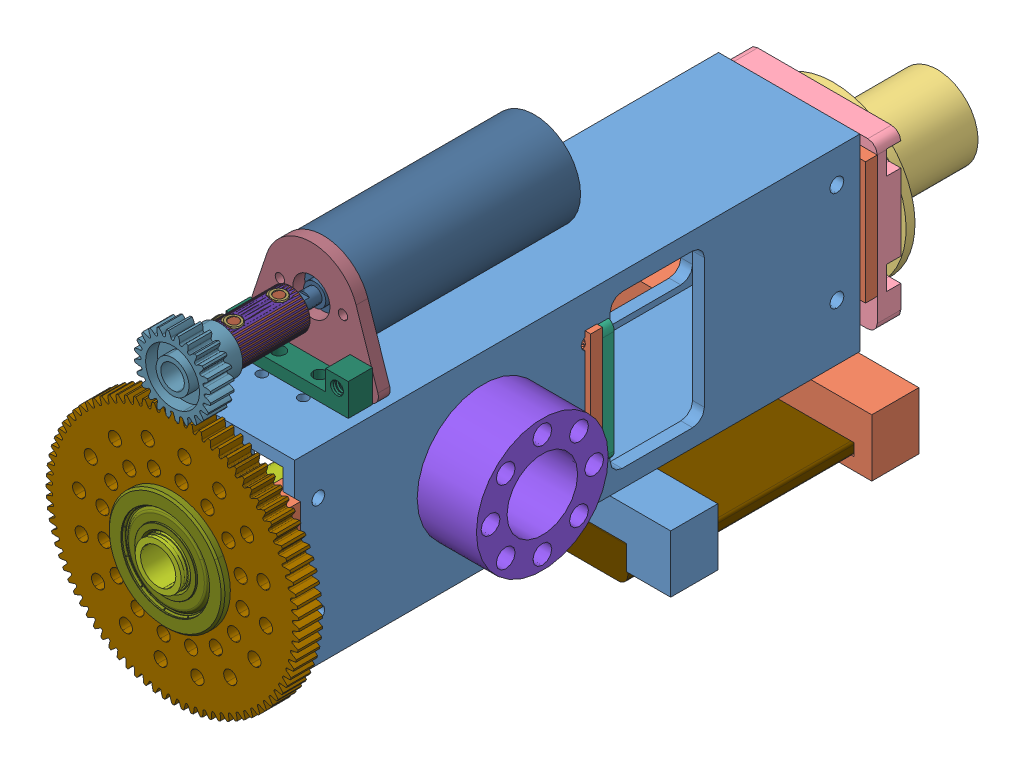
SolidWorks assembly L3v3 Assembly, configuration Default. Lengths in mm.
Overall size (93.13 102.39 210.1).
34 component instances, 20 part files, 64 mates.
Components (placement in the parent):
- L3v1 Base-1: L3v1 Base [Default] at (8.4803 58.2755 10.2579) x (1 0 0) z (0 -1 0) size (38.1 152.4 50.8)
- J2v2 Angle Bracket 585508-1: J2v2 Angle Bracket 585508 [Default] at (25.1173 61.4505 10.2579) x (0 -1 0) z (1 0 0) size (33.02 12.43 7.88)
- J2v2 Angle Bracket 585508-2: J2v2 Angle Bracket 585508 [Default] at (-8.1567 61.4505 10.2579) x (0 1 0) z (-1 0 0) size (33.02 12.43 7.88)
- 12 wire slip ring-1: 12 wire slip ring [Default] at (8.4803 58.2755 -1.6671) x (0.999999 -0.001711 0) z (-0.001711 -0.999999 0) size (44 39.4 44)
- L3v1 SlipRingBlock-2: L3v1 SlipRingBlock [Default] at (8.4803 58.2755 7.0829) x (-1 0 0) z (0 -1 0) size (41.15 6.35 44.45)
- 0.5 oilite bushing-1: 0.5 oilite bushing [6338K572] at (8.4803 58.2755 76.4249) x (1 0 0) z (0 -1 0) size (22.23 12.7 22.23)
- J2v2 Angle Bracket 585508-3: J2v2 Angle Bracket 585508 [Default] at (25.1173 58.2755 84.3624) x (0 -1 0) z (1 0 0) size (33.02 12.43 7.88)
- J2v2 Angle Bracket 585508-4: J2v2 Angle Bracket 585508 [Default] at (-8.1567 58.2755 84.3624) x (0 1 0) z (-1 0 0) size (33.02 12.43 7.88)
- L3v1 Bushing Support-1: L3v1 Bushing Support [Default] at (8.4803 58.2755 78.0124) x (1 0 0) z (0 -1 0) size (41.15 3.17 33.02)
- Link3 to 4 Shaft-1: Link3 to 4 Shaft [Default] at (8.4803 58.2755 127.4789) x (0 0 -1) z (0.966023 0.258455 0) size (105.92 12.45 12.45)
- L3v1 Spacer-1: L3v1 Spacer [Default] at (43.5069 58.2755 111.8579) x (0 1 0) z (0 0 1) size (35.56 15.98 35.56)
- 0.5 oilite bushing-2: 0.5 oilite bushing [6338K572] at (8.4803 58.2755 170.5954) x (1 0 0) z (0 1 0) size (22.23 12.7 22.23)
- 84T 32DP 1in bore plate gear-1: 84T 32DP 1in bore plate gear [Default] at (8.4803 58.2755 176.5517) x (-0.495933 -0.868361 0) z (0 0 -1) size (68.26 68.26 6.35)
- 56 rpm motor-1: 56 rpm motor [Default] at (8.4803 100.6135 135.9258) x (0 0 1) z (-1 0 0) size (74.8 24.8 24.8)
- 4mm to 6mm-1: 4mm to 6mm [Default] at (21.5273 122.4162 168.6055) x (0.389298 0.921112 0) z (-0.921112 0.389298 0) size (10.67 19.05 10.93)
  - 625220 assembly.STEP-1: 625220 assembly.STEP [Default] at origin size (10.67 19.05 10.93)
    - 625220.STEP-1: 625220.STEP [Default] at (-25.1618 4.7538 3.53) size (10.67 19.05 10.67)
    - 632134_91375A436.STEP-1: 632134_91375A436.STEP [Default] at (-25.1618 8.1828 7.9297) x (-0.317738 0.948179 0) z (0 0 1) size (4.83 4.83 3.18)
    - 632134_91375A436.STEP-2: 632134_91375A436.STEP [Default] at (-25.1618 20.3748 6.6171) x (0.993493 0.113893 0) z (0 0 1) size (4.83 4.83 3.18)
- L3v1 Bushing Support-2: L3v1 Bushing Support [Default] at (8.4803 58.2755 169.0079) x (1 0 0) z (0 1 0) size (41.15 3.17 33.02)
- L3 motor mount v2-2: L3 motor mount v2 [Default] at (8.4803 100.6135 139.1008) x (0 0 1) z (-1 0 0) size (3.17 29.64 36.13)
- J2v2 Angle Bracket 585508-9: J2v2 Angle Bracket 585508 [Default] at (-8.1567 58.2755 162.6579) x (0 -1 0) z (-1 0 0) size (33.02 12.43 7.88)
- J2v2 Angle Bracket 585508-10: J2v2 Angle Bracket 585508 [Default] at (25.1173 58.2755 162.6579) x (0 1 0) z (1 0 0) size (33.02 12.43 7.88)
- 24T quarter inch gear hub-1: 24T quarter inch gear hub [Default] at (18.8185 127.1627 171.0724) x (-0.383066 0.923721 0) z (0 0 1) size (20.64 20.64 12.7)
- DualPanelMountA-1: DualPanelMountA [Default] at (-8.0297 83.6755 139.1008) x (1 0 0) z (0 -1 0) size (33.02 6.58 8.63)
- .5ID 1.125OD Flange Bearing-1: .5ID 1.125OD Flange Bearing [Default] at (8.4803 58.2755 170.5954) x (-0.477964 0.87838 0) z (0.87838 0.477964 0) size (31.17 7.94 31.17)
- 4mm to .25in-1: 4mm to .25in [Default] at (94.8379 57.4084 170.9593) x (0.996664 -0.081613 0) z (0.081613 0.996664 0) size (10.67 19.05 10.67)
  - 625118 assembly.STEP-1: 625118 assembly.STEP [Default] at origin size (10.67 19.05 10.67)
    - 625118.STEP-1: 625118.STEP [Default] at (-89.5957 7.0024 36.013) size (10.67 19.05 10.67)
    - 632134_91375A436.STEP-1: 632134_91375A436.STEP [Default] at (-89.5957 10.4314 40.1568) x (0.259519 -0.965738 0) z (0 0 1) size (4.83 4.83 3.18)
    - 632134_91375A436.STEP-2: 632134_91375A436.STEP [Default] at (-89.5957 22.6234 40.1568) x (0.166108 -0.986108 0) z (0 0 1) size (4.83 4.83 3.18)
- SlidingMount-1: SlidingMount [Default] at (8.4803 23.9855 13.848) x (-1 0 0) z (0 1 0) size (60.96 76.2 10.16)
- camerasliderailstopper-1: camerasliderailstopper [Default] at (48.4853 32.8755 64.9589) x (0 0 1) z (1 0 0) size (12.7 15.49 70.87)
- camerasliderail-1: camerasliderail [Default] at (48.4853 32.8755 10.7246) x (0 0 1) z (1 0 0) size (12.7 15.49 70.87)
Mates (geometry in assembly coordinates):
- Coincident5: coincident anti-aligned: plane of L3v1 Base-1 through (8.4803 58.2755 10.2579) normal (0 0 -1); plane of J2v2 Angle Bracket 585508-1 through (25.1173 61.4505 10.2579) normal (0 0 1)
- Coincident7: coincident anti-aligned: plane of L3v1 Base-1 through (24.3553 36.0505 162.6579) normal (-1 0 0); plane of J2v2 Angle Bracket 585508-1 through (24.3553 51.0213 19.5136) normal (1 0 0)
- Coincident8: coincident anti-aligned: plane of L3v1 Base-1 through (-7.3947 36.0505 162.6579) normal (1 0 0); plane of J2v2 Angle Bracket 585508-2 through (-7.3947 71.8798 19.5136) normal (-1 0 0)
- Coincident9: coincident anti-aligned: plane of L3v1 Base-1 through (8.4803 58.2755 10.2579) normal (0 0 -1); plane of J2v2 Angle Bracket 585508-2 through (-8.1567 61.4505 10.2579) normal (0 0 1)
- Coincident10: coincident aligned: plane of J2v2 Angle Bracket 585508-1 through (29.0543 77.9605 7.0829) normal (0 1 0); plane of J2v2 Angle Bracket 585508-2 through (-12.0937 77.9605 7.0829) normal (0 1 0)
- Distance2: distance = 5.715 mm aligned: plane of J2v2 Angle Bracket 585508-1 through (29.0543 77.9605 7.0829) normal (0 1 0); plane of L3v1 Base-1 through (-10.5697 83.6755 162.6579) normal (0 1 0)
- Coincident16: coincident anti-aligned: plane of J2v2 Angle Bracket 585508-1 through (25.1173 61.4505 7.0829) normal (0 0 -1); plane of L3v1 SlipRingBlock-2 through (8.4803 58.2755 7.0829) normal (0 0 1)
- Concentric4: concentric anti-aligned: circle of J2v2 Angle Bracket 585508-1; cylinder of L3v1 SlipRingBlock-2 through (25.8793 74.9209 0.7329) axis (0 0 -1) radius 1.8986
- Concentric5: concentric anti-aligned: circle of J2v2 Angle Bracket 585508-2; circle of L3v1 SlipRingBlock-2
- Coincident17: coincident anti-aligned: plane of 12 wire slip ring-1 through (8.4803 58.2755 0.7329) normal (0 0 1); plane of L3v1 SlipRingBlock-2 through (8.4803 58.2755 0.7329) normal (0 0 -1)
- Concentric6: concentric anti-aligned: cylinder of 12 wire slip ring-1 through (8.4803 58.2755 -29.6671) axis (0 0 1) radius 11; cylinder of L3v1 SlipRingBlock-2 through (8.4803 58.2755 7.0829) axis (0 0 -1) radius 11.43
- Coincident22: coincident anti-aligned: plane of L3v1 Base-1 through (-7.3947 36.0505 162.6579) normal (1 0 0); plane of J2v2 Angle Bracket 585508-4 through (-7.3947 68.7048 93.6181) normal (-1 0 0)
- Width2: width aligned: plane of J2v2 Angle Bracket 585508-4 through (-12.0937 74.7855 81.1874) normal (0 1 0); plane of L3v1 Base-1 through (-12.0937 41.7655 81.1874) normal (0 -1 0); plane of J2v2 Angle Bracket 585508-4 through (-10.5697 83.6755 162.6579) normal (0 1 0); plane of L3v1 Base-1 through (-10.5697 32.8755 162.6579) normal (0 -1 0)
- Coincident24: coincident anti-aligned: plane of L3v1 Base-1 through (24.3553 36.0505 162.6579) normal (-1 0 0); plane of J2v2 Angle Bracket 585508-3 through (24.3553 68.7048 93.6181) normal (1 0 0)
- Coincident25: coincident aligned: plane of J2v2 Angle Bracket 585508-3 through (25.1173 58.2755 81.1874) normal (0 0 -1); plane of J2v2 Angle Bracket 585508-4 through (-8.1567 58.2755 81.1874) normal (0 0 -1)
- Coincident26: coincident aligned: plane of J2v2 Angle Bracket 585508-3 through (29.0543 74.7855 81.1874) normal (0 1 0); plane of J2v2 Angle Bracket 585508-4 through (-12.0937 74.7855 81.1874) normal (0 1 0)
- Coincident27: coincident anti-aligned: plane of J2v2 Angle Bracket 585508-4 through (-8.1567 58.2755 81.1874) normal (0 0 -1); plane of L3v1 Bushing Support-1 through (26.5143 72.2455 81.1874) normal (0 0 1)
- Width3: width anti-aligned: plane of L3v1 Bushing Support-1 through (26.5143 74.7855 81.1874) normal (0 1 0); plane of J2v2 Angle Bracket 585508-4 through (26.5143 41.7655 81.1874) normal (0 -1 0); plane of L3v1 Bushing Support-1 through (-12.0937 41.7655 81.1874) normal (0 -1 0); plane of J2v2 Angle Bracket 585508-4 through (-12.0937 74.7855 81.1874) normal (0 1 0)
- Coincident28: coincident aligned: plane of J2v2 Angle Bracket 585508-4 through (-12.0937 41.7655 81.1874) normal (-1 0 0); plane of L3v1 Bushing Support-1 through (-12.0937 44.3055 81.1874) normal (-1 0 0)
- Coincident29: coincident anti-aligned: plane of 0.5 oilite bushing-1 through (8.4803 58.2755 78.0124) normal (0 0 1); plane of L3v1 Bushing Support-1 through (26.5143 72.2455 78.0124) normal (0 0 -1)
- Concentric7: concentric anti-aligned: cylinder of 0.5 oilite bushing-1 through (8.4803 58.2755 89.1249) axis (0 0 -1) radius 6.3627; cylinder of L3v1 Bushing Support-1 through (8.4803 58.2755 78.0124) axis (0 0 1) radius 7.9502
- Concentric8: concentric anti-aligned: cylinder of 0.5 oilite bushing-1 through (8.4803 58.2755 89.1249) axis (0 0 -1) radius 6.3627; cylinder of Link3 to 4 Shaft-1 through (8.4803 58.2755 74.5199) axis (0 0 1) radius 6.223
- Coincident30: coincident aligned: plane of 0.5 oilite bushing-1 through (8.4803 58.2755 76.4249) normal (0 0 -1); plane of Link3 to 4 Shaft-1 through (8.4803 58.2755 76.4249) normal (0 0 -1)
- Coincident31: coincident anti-aligned: plane of L3v1 Base-1 through (27.5303 32.8755 162.6579) normal (1 0 0); plane of L3v1 Spacer-1 through (27.5303 58.2755 111.8579) normal (-1 0 0)
- Concentric9: concentric anti-aligned: cylinder of L3v1 Base-1 through (27.5303 58.2755 111.8579) axis (-1 0 0) radius 9.525; cylinder of L3v1 Spacer-1 through (27.5303 58.2755 111.8579) axis (1 0 0) radius 9.525
- Concentric10: concentric anti-aligned: cylinder of L3v1 Base-1 through (27.5303 48.3973 121.7362) axis (-1 0 0) radius 2.5527; cylinder of L3v1 Spacer-1 through (27.5303 48.3973 121.7362) axis (1 0 0) radius 2.5527
- Concentric15: concentric anti-aligned: cylinder of Link3 to 4 Shaft-1 through (8.4803 58.2755 74.5199) axis (0 0 1) radius 6.223; cylinder of 84T 32DP 1in bore plate gear-1 through (8.4803 58.2755 176.5517) axis (0 0 -1) radius 14.2875
- Concentric18: concentric aligned: cylinder of Link3 to 4 Shaft-1 through (8.4803 58.2755 74.5199) axis (0 0 1) radius 6.223; cylinder of 0.5 oilite bushing-2 through (8.4803 58.2755 157.8954) axis (0 0 1) radius 6.3627
- Concentric22: concentric anti-aligned: cylinder of Link3 to 4 Shaft-1 through (8.4803 58.2755 74.5199) axis (0 0 1) radius 6.223; cylinder of 84T 32DP 1in bore plate gear-1 through (8.4803 58.2755 176.5517) axis (0 0 -1) radius 14.2875
- Concentric24: concentric anti-aligned: cylinder of 56 rpm motor-1 through (8.4803 100.6135 153.7258) axis (0 0 -1) radius 2; cylinder of 4mm to 6mm-1/625220 assembly.STEP-1/625220.STEP-1 through (8.4803 100.6135 144.8017) axis (0 0 1) radius 5.334
- Coincident48: coincident aligned: circle of 56 rpm motor-1; circle of 4mm to 6mm-1/625220 assembly.STEP-1/625220.STEP-1
- Concentric25: concentric anti-aligned: cylinder of 0.5 oilite bushing-2 through (8.4803 58.2755 157.8954) axis (0 0 1) radius 7.9502; cylinder of L3v1 Bushing Support-2 through (8.4803 58.2755 169.0079) axis (0 0 -1) radius 7.9502
- Parallel5: parallel aligned: plane of 12 wire slip ring-1 through (8.4803 58.2755 -29.6671) normal (0 0 -1); plane of 56 rpm motor-1 through (8.4803 100.6135 78.9258) normal (0 0 -1)
- Concentric28: concentric anti-aligned: cylinder of 56 rpm motor-1 through (8.4803 100.6135 138.2258) axis (0 0 -1) radius 3; cylinder of L3 motor mount v2-2 through (8.4803 100.6135 135.9258) axis (0 0 1) radius 5
- Concentric29: concentric aligned: cylinder of 56 rpm motor-1 through (-0.0197 100.6135 130.9258) axis (0 0 1) radius 1.27; cylinder of L3 motor mount v2-2 through (-0.0197 100.6135 135.9258) axis (0 0 1) radius 1.27
- Coincident62: coincident anti-aligned: plane of 56 rpm motor-1 through (8.4803 100.6135 135.9258) normal (0 0 1); plane of L3 motor mount v2-2 through (8.4803 100.6135 135.9258) normal (0 0 -1)
- Coincident64: coincident anti-aligned: plane of L3v1 Base-1 through (-10.5697 83.6755 162.6579) normal (0 1 0); plane of L3 motor mount v2-2 through (8.4803 83.6755 135.9258) normal (0 -1 0)
- Symmetric6: symmetric aligned: plane of L3v1 Base-1 through (27.5303 32.8755 162.6579) normal (1 0 0); plane of L3v1 Base-1 through (-10.5697 32.8755 162.6579) normal (-1 0 0); plane of 56 rpm motor-1 through (8.4803 100.6135 135.9258) normal (-1 0 0)
- Coincident68: coincident anti-aligned: plane of L3v1 Base-1 through (-7.3947 36.0505 162.6579) normal (1 0 0); plane of J2v2 Angle Bracket 585508-9 through (-7.3947 68.7048 153.4021) normal (-1 0 0)
- Coincident69: coincident aligned: plane of L3v1 Bushing Support-2 through (26.5143 74.7855 165.8329) normal (0 1 0); plane of J2v2 Angle Bracket 585508-9 through (-12.0937 74.7855 165.8329) normal (0 1 0)
- Coincident70: coincident anti-aligned: plane of L3v1 Base-1 through (8.4803 58.2755 162.6579) normal (0 0 1); plane of J2v2 Angle Bracket 585508-9 through (-8.1567 58.2755 162.6579) normal (0 0 -1)
- Coincident71: coincident anti-aligned: plane of L3v1 Base-1 through (24.3553 36.0505 162.6579) normal (-1 0 0); plane of J2v2 Angle Bracket 585508-10 through (24.3553 68.7048 153.4021) normal (1 0 0)
- Coincident72: coincident aligned: plane of L3v1 Bushing Support-2 through (26.5143 74.7855 165.8329) normal (0 1 0); plane of J2v2 Angle Bracket 585508-10 through (29.0543 74.7855 165.8329) normal (0 1 0)
- Coincident73: coincident anti-aligned: plane of L3v1 Base-1 through (8.4803 58.2755 162.6579) normal (0 0 1); plane of J2v2 Angle Bracket 585508-10 through (25.1173 58.2755 162.6579) normal (0 0 -1)
- Concentric30: concentric aligned: circle of 4mm to 6mm-1/625220 assembly.STEP-1/625220.STEP-1; circle of 24T quarter inch gear hub-1
- Coincident74: coincident anti-aligned: plane of 4mm to 6mm-1/625220 assembly.STEP-1/625220.STEP-1 through (8.4803 100.6135 163.8517) normal (0 0 1); plane of 24T quarter inch gear hub-1 through (8.4803 100.6135 163.8517) normal (0 0 -1)
- Coincident77: coincident anti-aligned: plane of L3v1 Base-1 through (-10.5697 83.6755 162.6579) normal (0 1 0); plane of DualPanelMountA-1 through (-8.0297 83.6755 145.6794) normal (0 -1 0)
- Width5: width anti-aligned: plane of L3v1 Base-1 through (-10.5697 32.8755 162.6579) normal (-1 0 0); plane of L3v1 Base-1 through (27.5303 32.8755 162.6579) normal (1 0 0); plane of DualPanelMountA-1 through (24.9903 83.6755 145.6794) normal (1 0 0); plane of DualPanelMountA-1 through (-8.0297 92.3039 145.6794) normal (-1 0 0)
- Coincident78: coincident anti-aligned: plane of L3 motor mount v2-2 through (8.4803 100.6135 139.1008) normal (0 0 1); plane of DualPanelMountA-1 through (-8.0297 83.6755 139.1008) normal (0 0 -1)
- Coincident79: coincident aligned: plane of 84T 32DP 1in bore plate gear-1 through (-20.5808 75.4204 176.5517) normal (0 0 1); plane of 24T quarter inch gear hub-1 through (-0.5025 96.3759 176.5517) normal (0 0 1)
- Concentric31: concentric aligned: cylinder of 84T 32DP 1in bore plate gear-1 through (8.4803 58.2755 176.5517) axis (0 0 -1) radius 14.2875; cylinder of .5ID 1.125OD Flange Bearing-1 through (8.4803 58.2755 176.5517) axis (0 0 -1) radius 14.2875
- Coincident80: coincident anti-aligned: plane of 84T 32DP 1in bore plate gear-1 through (-20.5808 75.4204 176.5517) normal (0 0 1); plane of .5ID 1.125OD Flange Bearing-1 through (8.4803 58.2755 176.5517) normal (0 0 -1)
- Coincident81: coincident aligned: plane of Link3 to 4 Shaft-1 through (8.4803 58.2755 178.5329) normal (0 0 1); plane of .5ID 1.125OD Flange Bearing-1 through (8.4803 58.2755 178.5329) normal (0 0 1)
- Coincident82: coincident anti-aligned: plane of 0.5 oilite bushing-2 through (8.4803 58.2755 170.5954) normal (0 0 1); plane of .5ID 1.125OD Flange Bearing-1 through (8.4803 58.2755 170.5954) normal (0 0 -1)
- Coincident84: coincident anti-aligned: plane of 0.5 oilite bushing-2 through (8.4803 58.2755 169.0079) normal (0 0 -1); plane of L3v1 Bushing Support-2 through (26.5143 44.3055 169.0079) normal (0 0 1)
- Coincident85: coincident anti-aligned: plane of L3v1 Bushing Support-2 through (26.5143 44.3055 165.8329) normal (0 0 -1); plane of J2v2 Angle Bracket 585508-9 through (-8.1567 58.2755 165.8329) normal (0 0 1)
- Concentric34: concentric aligned: cylinder of 56 rpm motor-1 through (8.4803 100.6135 153.7258) axis (0 0 -1) radius 2; cylinder of 4mm to .25in-1/625118 assembly.STEP-1/625118.STEP-1 through (8.4803 100.6135 144.9068) axis (0 0 -1) radius 2
- Coincident86: coincident aligned: circle of 56 rpm motor-1; circle of 4mm to .25in-1/625118 assembly.STEP-1/625118.STEP-1
- Width6: width anti-aligned: plane of camerasliderailstopper-1 through (39.0873 23.9855 77.6589) normal (-1 0 0); plane of camerasliderailstopper-1 through (-22.1267 23.9855 77.6589) normal (1 0 0); plane of SlidingMount-1 through (38.9603 23.9855 77.348) normal (1 0 0); plane of SlidingMount-1 through (-21.9997 23.9855 77.348) normal (-1 0 0)
- Coincident89: coincident anti-aligned: plane of SlidingMount-1 through (38.9603 23.9855 77.348) normal (0 1 0); plane of camerasliderailstopper-1 through (-22.6347 23.9855 77.6589) normal (0 -1 0)
- Width7: width aligned: plane of L3v1 Base-1 through (-10.5697 32.8755 162.6579) normal (-1 0 0); plane of L3v1 Base-1 through (27.5303 32.8755 162.6579) normal (1 0 0); plane of camerasliderailstopper-1 through (-26.9527 17.3815 77.6599) normal (-1 0 0); plane of camerasliderailstopper-1 through (43.9133 17.3815 77.6599) normal (1 0 0)
- Width8: width aligned: plane of L3v1 Base-1 through (-10.5697 32.8755 162.6579) normal (-1 0 0); plane of L3v1 Base-1 through (27.5303 32.8755 162.6579) normal (1 0 0); plane of camerasliderail-1 through (-26.9527 17.3815 23.4256) normal (-1 0 0); plane of camerasliderail-1 through (43.9133 17.3815 23.4256) normal (1 0 0)
- Coincident90: coincident anti-aligned: plane of SlidingMount-1 through (38.9603 23.9855 77.348) normal (0 1 0); plane of camerasliderail-1 through (-22.6347 23.9855 23.4246) normal (0 -1 0)
- Coincident91: coincident anti-aligned: plane of L3v1 Base-1 through (-10.5697 32.8755 162.6579) normal (0 -1 0); plane of camerasliderailstopper-1 through (48.4853 32.8755 77.6589) normal (0 1 0)
